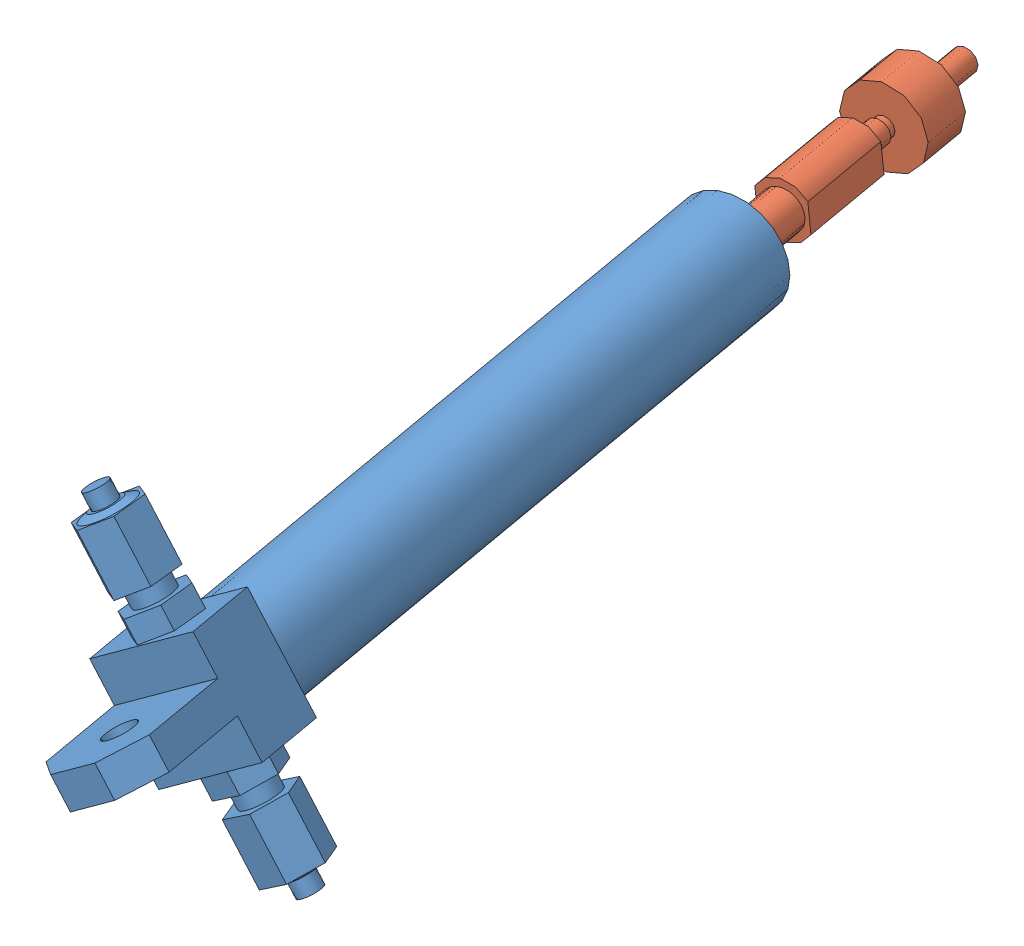
SolidWorks assembly Cilindro_hidraulico, configuration Valor predeterminado. Lengths in mm.
Overall size (80.99 75.67 284.21).
2 component instances, 2 part files, 1 mates.
Components (placement in the parent):
- INTF_1_2-2: INTF_1_2 [Valor predeterminado] at (127.4874 -176.1214 -201.3756) size (70.31 75.67 209.33)
- INTF_1_8-2: INTF_1_8 [Valor predeterminado] at (14.303 -53.5846 -156.297) x (0.077983 -0.983609 0.162577) z (0.162577 0.173437 0.971333) size (39.86 20 157.48)
Mates (geometry in assembly coordinates):
- Concêntrico1: concentric anti-aligned: cylinder of INTF_1_2-2 through (123.5605 -52.1889 -250.8384) axis (0.173648 0 0.984808) radius 5; cylinder of INTF_1_8-2 through (138.0916 -52.1889 -168.4287) axis (-0.173648 0 -0.984808) radius 5
